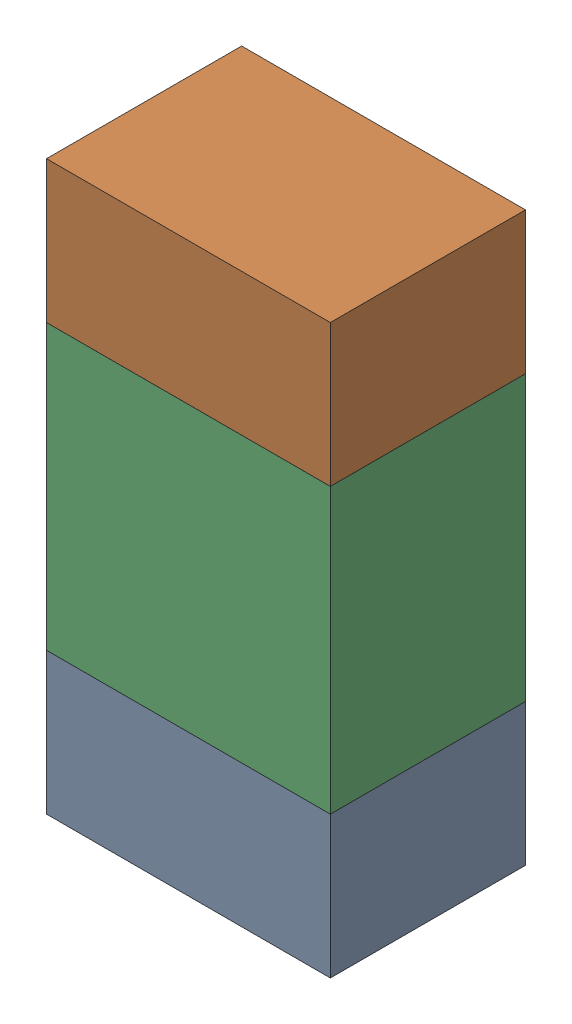
SolidWorks assembly R37, configuration ﾃﾞﾌｫﾙﾄ. Lengths in mm.
Overall size (0.8 1.6 0.55).
6 component instances, 2 part files, 0 mates.
Components (placement in the parent):
- 689261784-1: 689261784 [ﾃﾞﾌｫﾙﾄ] at (28.4999 69.1501 0) size (0.8 0.4 0.55)
  - Extruded_34-1: Extruded_34 [ﾃﾞﾌｫﾙﾄ] at origin size (0.8 0.4 0.55)
- 689261784-2: 689261784 [ﾃﾞﾌｫﾙﾄ] at (28.4999 70.3501 0) size (0.8 0.4 0.55)
  - Extruded_34-1: Extruded_34 [ﾃﾞﾌｫﾙﾄ] at origin size (0.8 0.4 0.55)
- 689261648-1: 689261648 [ﾃﾞﾌｫﾙﾄ] at (28.4999 69.75 0) size (0.8 0.8 0.55)
  - Extruded_33-1: Extruded_33 [ﾃﾞﾌｫﾙﾄ] at origin size (0.8 0.8 0.55)
